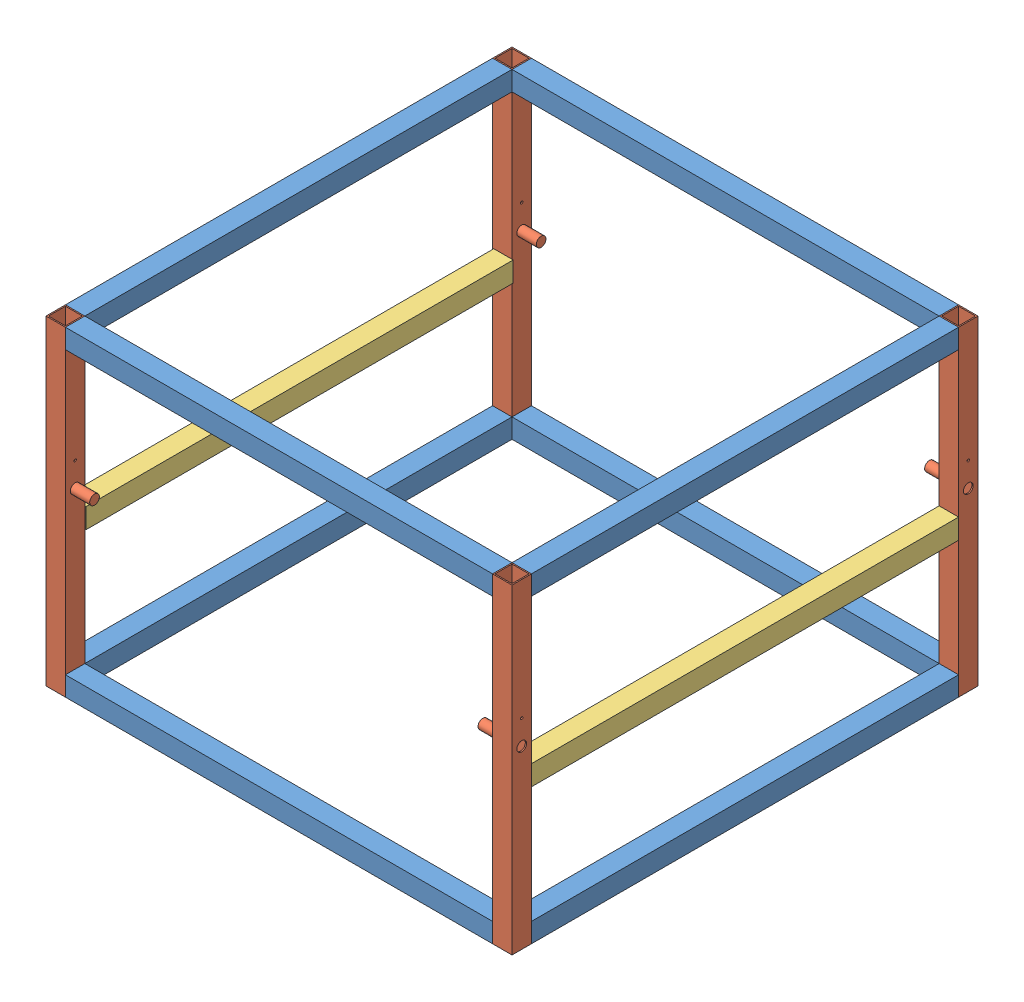
SolidWorks assembly Level 3, configuration Default. Lengths in mm.
Overall size (1219.2 838.2 1219.2).
14 component instances, 3 part files, 41 mates.
Components (placement in the parent):
- Level 3 Bottom&Top-1: Level 3 Bottom&Top [Default] at (530.5221 530.5559 820.4186) size (50.8 50.8 1117.6)
- Level 3 Left&Right-1: Level 3 Left&Right [Default] at (581.3221 924.2559 236.2186) x (-1 0 0) z (0 0 -1) size (101.6 838.2 50.8)
- Level 3 Left&Right-2: Level 3 Left&Right [Default] at (581.3221 924.2559 1404.6186) x (-1 0 0) z (0 0 -1) size (101.6 838.2 50.8)
- Level 3 Bottom&Top-2: Level 3 Bottom&Top [Default] at (530.5221 1317.9559 820.4186) size (50.8 50.8 1117.6)
- Level 3 Bottom&Top-3: Level 3 Bottom&Top [Default] at (-28.2779 530.5559 1430.0186) x (0 0 -1) z (1 0 0) size (50.8 50.8 1117.6)
- Level 3 Bottom&Top-4: Level 3 Bottom&Top [Default] at (-28.2779 1317.9559 1430.0186) x (0 0 -1) z (1 0 0) size (50.8 50.8 1117.6)
- Level 3 Bottom&Top-5: Level 3 Bottom&Top [Default] at (-28.2779 1292.5559 236.2186) x (0 1 0) z (1 0 0) size (50.8 50.8 1117.6)
- Level 3 Bottom&Top-6: Level 3 Bottom&Top [Default] at (-28.2779 555.9559 236.2186) x (0 -1 0) z (1 0 0) size (50.8 50.8 1117.6)
- Level 3 Bottom&Top-9: Level 3 Bottom&Top [Default] at (-637.8779 1317.9559 820.4186) size (50.8 50.8 1117.6)
- Level 3 Left&Right-5: Level 3 Left&Right [Default] at (-637.8779 924.2559 1404.6186) size (101.6 838.2 50.8)
- Level 3 Left&Right-6: Level 3 Left&Right [Default] at (-637.8779 924.2559 236.2186) size (101.6 838.2 50.8)
- Level 3 Bottom&Top-10: Level 3 Bottom&Top [Default] at (-637.8779 530.5559 820.4186) size (50.8 50.8 1117.6)
- Level 3 Brace-4: Level 3 Brace [Default] at (555.9221 887.0074 261.6186) size (50.8 52.5 1117.6)
- Level 3 Brace-5: Level 3 Brace [Default] at (-609.3029 887.0074 261.6186) size (50.8 52.5 1117.6)
Mates (geometry in assembly coordinates):
- Coincident53: coincident anti-aligned: plane of Level 3 Bottom&Top-3 through (-587.0779 555.9559 1379.2186) normal (-1 0 0); plane of Level 3 Left&Right-5 through (-587.0779 924.2559 1404.6186) normal (1 0 0)
- Coincident54: coincident aligned: plane of Level 3 Bottom&Top-3 through (-28.2779 530.5559 1430.0186) normal (0 0 1); plane of Level 3 Left&Right-5 through (-587.0779 505.1559 1430.0186) normal (0 0 1)
- Coincident55: coincident aligned: plane of Level 3 Bottom&Top-3 through (530.5221 505.1559 1379.2186) normal (0 -1 0); plane of Level 3 Left&Right-5 through (-587.0779 505.1559 1379.2186) normal (0 -1 0)
- Coincident56: coincident anti-aligned: plane of Level 3 Bottom&Top-4 through (-587.0779 1343.3559 1379.2186) normal (-1 0 0); plane of Level 3 Left&Right-5 through (-587.0779 924.2559 1404.6186) normal (1 0 0)
- Coincident57: coincident aligned: plane of Level 3 Bottom&Top-4 through (-28.2779 1317.9559 1430.0186) normal (0 0 1); plane of Level 3 Left&Right-5 through (-587.0779 505.1559 1430.0186) normal (0 0 1)
- Coincident58: coincident aligned: plane of Level 3 Bottom&Top-4 through (530.5221 1343.3559 1379.2186) normal (0 1 0); plane of Level 3 Left&Right-5 through (-587.0779 1343.3559 1379.2186) normal (0 1 0)
- Coincident59: coincident anti-aligned: plane of Level 3 Left&Right-2 through (530.5221 924.2559 1404.6186) normal (-1 0 0); plane of Level 3 Bottom&Top-3 through (530.5221 555.9559 1379.2186) normal (1 0 0)
- Coincident60: coincident aligned: plane of Level 3 Left&Right-2 through (530.5221 505.1559 1430.0186) normal (0 0 1); plane of Level 3 Bottom&Top-3 through (-28.2779 530.5559 1430.0186) normal (0 0 1)
- Coincident62: coincident aligned: plane of Level 3 Left&Right-2 through (530.5221 505.1559 1430.0186) normal (0 -1 0); plane of Level 3 Bottom&Top-3 through (530.5221 505.1559 1379.2186) normal (0 -1 0)
- Coincident63: coincident anti-aligned: plane of Level 3 Bottom&Top-1 through (581.3221 555.9559 1379.2186) normal (0 0 1); plane of Level 3 Left&Right-2 through (530.5221 505.1559 1379.2186) normal (0 0 -1)
- Coincident64: coincident aligned: plane of Level 3 Bottom&Top-1 through (581.3221 530.5559 820.4186) normal (1 0 0); plane of Level 3 Left&Right-2 through (581.3221 924.2559 1404.6186) normal (1 0 0)
- Coincident65: coincident: plane of Level 3 Bottom&Top-1 through (581.3221 505.1559 1379.2186) normal (0 -1 0); line of Level 3 Left&Right-2 through (581.3221 505.1559 1379.2186) axis (0 0 1)
- Coincident66: coincident anti-aligned: plane of Level 3 Left&Right-2 through (530.5221 505.1559 1379.2186) normal (0 0 -1); plane of Level 3 Bottom&Top-2 through (581.3221 1343.3559 1379.2186) normal (0 0 1)
- Coincident67: coincident aligned: plane of Level 3 Bottom&Top-2 through (581.3221 1343.3559 1379.2186) normal (0 1 0); plane of Level 3 Bottom&Top-4 through (530.5221 1343.3559 1379.2186) normal (0 1 0)
- Coincident68: coincident aligned: plane of Level 3 Left&Right-2 through (581.3221 924.2559 1404.6186) normal (1 0 0); plane of Level 3 Bottom&Top-2 through (581.3221 1317.9559 820.4186) normal (1 0 0)
- Coincident69: coincident anti-aligned: plane of Level 3 Left&Right-1 through (530.5221 924.2559 236.2186) normal (-1 0 0); plane of Level 3 Bottom&Top-5 through (530.5221 1343.3559 261.6186) normal (1 0 0)
- Coincident70: coincident anti-aligned: plane of Level 3 Left&Right-1 through (530.5221 924.2559 236.2186) normal (-1 0 0); plane of Level 3 Bottom&Top-6 through (530.5221 505.1559 210.8186) normal (1 0 0)
- Coincident72: coincident aligned: plane of Level 3 Left&Right-1 through (530.5221 505.1559 261.6186) normal (0 0 1); plane of Level 3 Bottom&Top-5 through (530.5221 1343.3559 261.6186) normal (0 0 1)
- Coincident73: coincident aligned: plane of Level 3 Left&Right-1 through (530.5221 1343.3559 261.6186) normal (0 1 0); plane of Level 3 Bottom&Top-5 through (-28.2779 1343.3559 236.2186) normal (0 1 0)
- Coincident74: coincident anti-aligned: plane of Level 3 Left&Right-1 through (530.5221 505.1559 261.6186) normal (0 0 1); plane of Level 3 Bottom&Top-2 through (581.3221 1343.3559 261.6186) normal (0 0 -1)
- Coincident75: coincident: line of Level 3 Left&Right-1 through (578.1471 1343.3559 258.4436) axis (0 0 -1); plane of Level 3 Bottom&Top-2 through (581.3221 1343.3559 1379.2186) normal (0 1 0)
- Coincident76: coincident aligned: plane of Level 3 Left&Right-1 through (581.3221 924.2559 236.2186) normal (1 0 0); plane of Level 3 Bottom&Top-2 through (581.3221 1317.9559 820.4186) normal (1 0 0)
- Coincident77: coincident anti-aligned: plane of Level 3 Left&Right-1 through (530.5221 924.2559 236.2186) normal (-1 0 0); plane of Level 3 Bottom&Top-6 through (530.5221 505.1559 210.8186) normal (1 0 0)
- Coincident79: coincident aligned: plane of Level 3 Left&Right-1 through (530.5221 505.1559 210.8186) normal (0 0 -1); plane of Level 3 Bottom&Top-6 through (530.5221 505.1559 210.8186) normal (0 0 -1)
- Coincident80: coincident aligned: plane of Level 3 Bottom&Top-1 through (581.3221 505.1559 1379.2186) normal (0 -1 0); plane of Level 3 Bottom&Top-6 through (-28.2779 505.1559 236.2186) normal (0 -1 0)
- Coincident81: coincident anti-aligned: plane of Level 3 Bottom&Top-6 through (-587.0779 505.1559 210.8186) normal (-1 0 0); plane of Level 3 Left&Right-6 through (-587.0779 924.2559 236.2186) normal (1 0 0)
- Coincident82: coincident aligned: plane of Level 3 Left&Right-6 through (-637.8779 924.2559 236.2186) normal (-1 0 0); plane of Level 3 Bottom&Top-10 through (-637.8779 530.5559 820.4186) normal (-1 0 0)
- Coincident83: coincident aligned: plane of Level 3 Bottom&Top-6 through (-28.2779 505.1559 236.2186) normal (0 -1 0); plane of Level 3 Left&Right-6 through (-587.0779 505.1559 210.8186) normal (0 -1 0)
- Coincident84: coincident: line of Level 3 Bottom&Top-6 through (-587.0779 555.9559 210.8186) axis (1 0 0); plane of Level 3 Left&Right-6 through (-587.0779 505.1559 210.8186) normal (0 0 -1)
- Coincident85: coincident anti-aligned: plane of Level 3 Bottom&Top-9 through (-587.0779 1343.3559 1379.2186) normal (0 0 1); plane of Level 3 Left&Right-5 through (-587.0779 505.1559 1379.2186) normal (0 0 -1)
- Coincident86: coincident aligned: plane of Level 3 Bottom&Top-9 through (-637.8779 1317.9559 820.4186) normal (-1 0 0); plane of Level 3 Left&Right-5 through (-637.8779 924.2559 1404.6186) normal (-1 0 0)
- Coincident87: coincident aligned: plane of Level 3 Bottom&Top-4 through (530.5221 1343.3559 1379.2186) normal (0 1 0); plane of Level 3 Bottom&Top-9 through (-587.0779 1343.3559 1379.2186) normal (0 1 0)
- Coincident88: coincident anti-aligned: plane of Level 3 Left&Right-5 through (-587.0779 505.1559 1379.2186) normal (0 0 -1); plane of Level 3 Bottom&Top-10 through (-587.0779 555.9559 1379.2186) normal (0 0 1)
- Coincident89: coincident aligned: plane of Level 3 Left&Right-5 through (-637.8779 924.2559 1404.6186) normal (-1 0 0); plane of Level 3 Bottom&Top-10 through (-637.8779 530.5559 820.4186) normal (-1 0 0)
- Coincident90: coincident aligned: plane of Level 3 Left&Right-5 through (-587.0779 505.1559 1379.2186) normal (0 -1 0); plane of Level 3 Bottom&Top-10 through (-587.0779 505.1559 1379.2186) normal (0 -1 0)
- Coincident94: coincident: plane of Level 3 Left&Right-1 through (581.3221 924.2559 236.2186) normal (1 0 0); plane of Level 3 Brace-4 through (581.3221 860.7559 1452.2748) normal (1 0 0)
- Distance2: distance = 355.6 mm: plane of Level 3 Brace-4 through (581.3221 860.7559 1452.2748) normal (0 -1 0); plane of Level 3 Bottom&Top-1 through (581.3221 505.1559 1379.2186) normal (0 -1 0)
- Coincident96: coincident anti-aligned: plane of Level 3 Left&Right-1 through (530.5221 505.1559 261.6186) normal (0 0 1); plane of Level 3 Brace-4 through (555.9221 887.0074 261.6186) normal (0 0 -1)
- Coincident97: coincident: plane of Level 3 Brace-4 through (581.3221 913.2589 1452.2748) normal (0 1 0); plane of Level 3 Brace-5 through (-583.9029 913.2589 1452.2748) normal (0 1 0)
- Coincident98: coincident: plane of Level 3 Left&Right-5 through (-587.0779 505.1559 1379.2186) normal (0 0 -1); plane of Level 3 Brace-5 through (-609.3029 887.0074 1379.2186) normal (0 0 1)
- Coincident99: coincident: line of Level 3 Left&Right-6 through (-634.7029 505.1559 258.4436) axis (0 1 0); plane of Level 3 Brace-5 through (-634.7029 860.7559 1452.2748) normal (-1 0 0)
